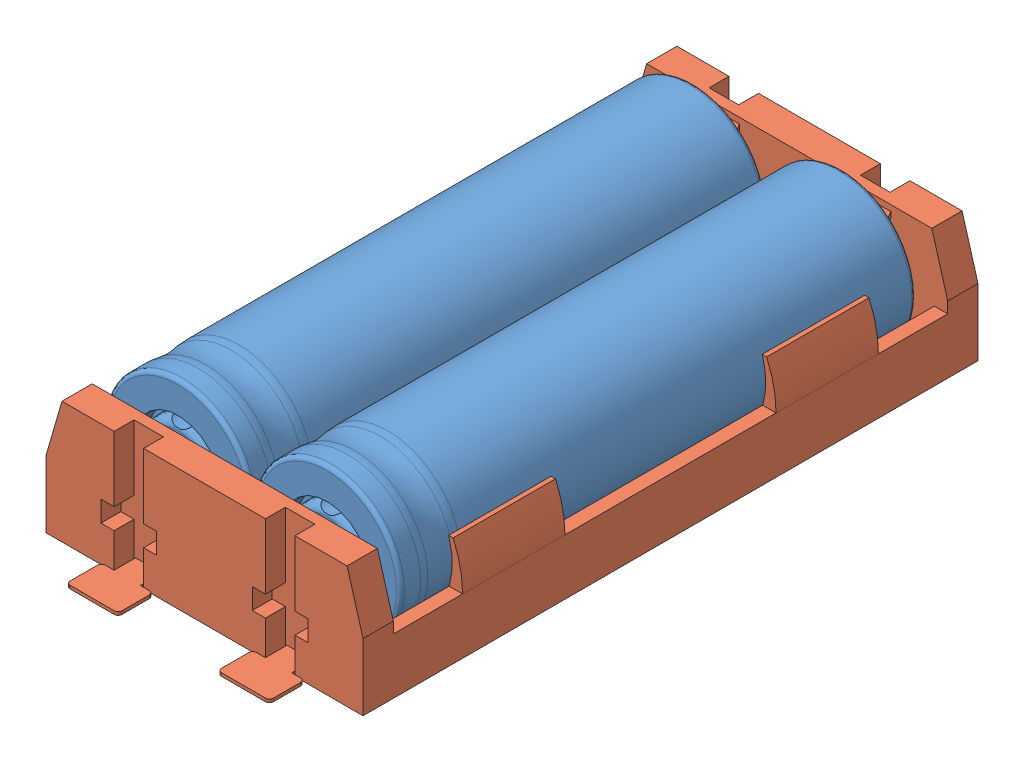
SolidWorks assembly 18650 battery holder, configuration Výchozí. Lengths in mm.
Overall size (39.8 18.9 86.4).
3 component instances, 2 part files, 4 mates.
Components (placement in the parent):
- 18650 baterie-1: 18650 baterie [Výchozí] at (-5.3689 1.7057 32.3879) size (18.5 18.5 64.78)
- 18650 holder 2x-1: 18650 holder 2x [Výchozí] at (-14.7189 1.7057 25.8879) size (39.8 15.3 86.4)
- 18650 baterie-2: 18650 baterie [Výchozí] at (-24.0689 1.7057 32.3879) size (18.5 18.5 64.78)
Mates (geometry in assembly coordinates):
- Sjednocená1: coincident: plane of 18650 baterie-1 through (-5.3689 1.7057 97.0879) normal (0 0 1); plane of 18650 baterie-2 through (-24.0689 1.7057 97.0879) normal (0 0 1)
- Soustředná1: concentric: cylinder of 18650 baterie-1 through (-5.3689 1.7057 97.0879) axis (0 0 -1) radius 9.25; cylinder of 18650 holder 2x-1 through (-5.3689 1.7057 135.2813) axis (0 0 -1) radius 9.25
- Soustředná2: concentric: cylinder of 18650 holder 2x-1 through (-24.0689 1.7057 135.2813) axis (0 0 -1) radius 9.25; cylinder of 18650 baterie-2 through (-24.0689 1.7057 97.0879) axis (0 0 -1) radius 9.25
- Vzdálenost2: distance = 6 mm: plane of 18650 holder 2x-1 through (-14.7189 1.7057 103.0879) normal (0 0 1); plane of 18650 baterie-1 through (-5.3689 1.7057 97.0879) normal (0 0 1)
